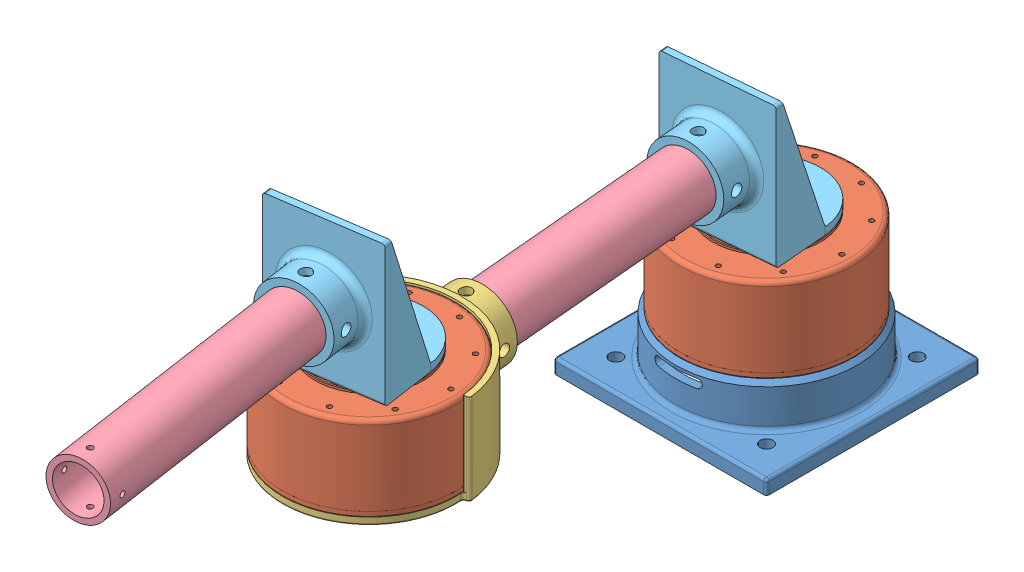
SolidWorks assembly Assembly_SCARA, configuration Default. Lengths in mm.
Overall size (175.34 283.02 625.11).
8 component instances, 5 part files, 16 mates.
Components (placement in the parent):
- base_link_X10-1: base_link_X10 [По умолчанию] at (81.3757 88.1097 90.3224) size (150 40 150)
- RMD-X10-S2-V3-1: RMD-X10-S2-V3 [По умолчанию] at (81.3757 180.7097 90.3224) x (0 0 -1) z (0 -1 0) size (122 122 74)
- RMD-X10-S2-V3-2: RMD-X10-S2-V3 [По умолчанию] at (108.5933 263.2097 397.1175) x (-0.97465 -0.000367 -0.223736) z (0.000384 -1 -0.000034) size (122 122 74)
- corner_back_muft_X10-1: corner_back_muft_X10 [По умолчанию] at (108.6154 205.6097 397.1155) x (0.996085 0.000386 -0.088398) z (0.088398 0 0.996085) size (129.94 64 146)
- tube-1: tube [По умолчанию] at (102.8565 239.6097 332.3711) x (-0.088398 0 -0.996085) z (-0.000384 1 0.000034) size (200 40 45)
- corner_scara_muft_X10-1: corner_scara_muft_X10 [По умолчанию] at (115.8678 189.6097 49.1121) x (0.088398 0 0.996085) z (-0.996085 0 0.088398) size (101 99 76)
- corner_scara_muft_X10-2: corner_scara_muft_X10 [По умолчанию] at (140.6114 272.1235 353.9597) x (0.146532 0.000023 0.989206) z (-0.989206 -0.000385 0.146532) size (101 99 76)
- tube-2: tube [По умолчанию] at (144.178 322.1152 637.4965) x (-0.146532 -0.000023 -0.989206) z (-0.000384 1 0.000034) size (200 40 45)
Mates (geometry in assembly coordinates):
- Концентричный1: concentric anti-aligned: circle of First link-1; circle of RMD-X10-S2-V3-1
- Концентричный2: concentric anti-aligned: circle of First link-1; circle of RMD-X10-S2-V3-1
- Совпадение1: coincident anti-aligned: plane of First link-1 through (81.3757 128.1097 90.3224) normal (0 1 0); plane of RMD-X10-S2-V3-1 through (141.3757 128.1097 90.3224) normal (0 -1 0)
- Концентричный9: concentric anti-aligned: cylinder of RMD-X10-S2-V3-2 through (96.7557 210.0034 448.7721) axis (0.000384 -1 -0.000034) radius 1.65; circle of corner_back-1
- Концентричный10: concentric anti-aligned: cylinder of RMD-X10-S2-V3-2 through (129.3833 210.0161 445.8766) axis (0.000384 -1 -0.000034) radius 1.65; circle of corner_back-1
- Совпадение4: coincident anti-aligned: plane of RMD-X10-S2-V3-2 through (122.0376 210.6169 338.6367) normal (0.000384 -1 -0.000034); plane of corner_back-1 through (108.6135 210.6097 397.1157) normal (-0.000384 1 0.000034)
- Совпадение11: coincident: circle of corner_back-1; circle of tube-1
- Концентричный16: concentric anti-aligned: cylinder of corner_back-1 through (113.9947 239.6097 457.8789) axis (-0.088398 0 -0.996085) radius 25; cylinder of tube-1 through (85.1768 239.6097 133.1541) axis (0.088398 0 0.996085) radius 16
- Концентричный18: concentric anti-aligned: circle of RMD-X10-S2-V3-1; circle of corner_scara-1
- Совпадение12: coincident anti-aligned: plane of RMD-X10-S2-V3-1 through (81.3757 189.6097 90.3224) normal (0 1 0); plane of corner_scara-1 through (46.8836 189.6097 131.5328) normal (0 -1 0)
- Концентричный19: concentric anti-aligned: circle of RMD-X10-S2-V3-2; circle of corner_scara-2
- Совпадение13: coincident anti-aligned: plane of RMD-X10-S2-V3-2 through (108.5898 272.1097 397.1178) normal (-0.000384 1 0.000034); plane of corner_scara-2 through (76.5683 272.096 440.2758) normal (0.000384 -1 -0.000034)
- Концентричный20: concentric anti-aligned: cylinder of tube-1 through (85.1768 239.6097 133.1541) axis (0.088398 0 0.996085) radius 16; cylinder of corner_scara-1 through (86.9448 239.6097 153.0758) axis (-0.088398 0 -0.996085) radius 25
- Совпадение14: coincident anti-aligned: plane of tube-1 through (85.1768 239.6097 133.1541) normal (-0.088398 0 -0.996085); circle of corner_scara-1
- Концентричный21: concentric anti-aligned: cylinder of corner_scara-2 through (117.8022 322.1112 459.4395) axis (-0.146532 -0.000023 -0.989206) radius 25; cylinder of tube-2 through (114.8715 322.1107 439.6554) axis (0.146532 0.000023 0.989206) radius 16
- Совпадение15: coincident anti-aligned: circle of corner_scara-2; plane of tube-2 through (114.8715 322.1107 439.6554) normal (-0.146532 -0.000023 -0.989206)
